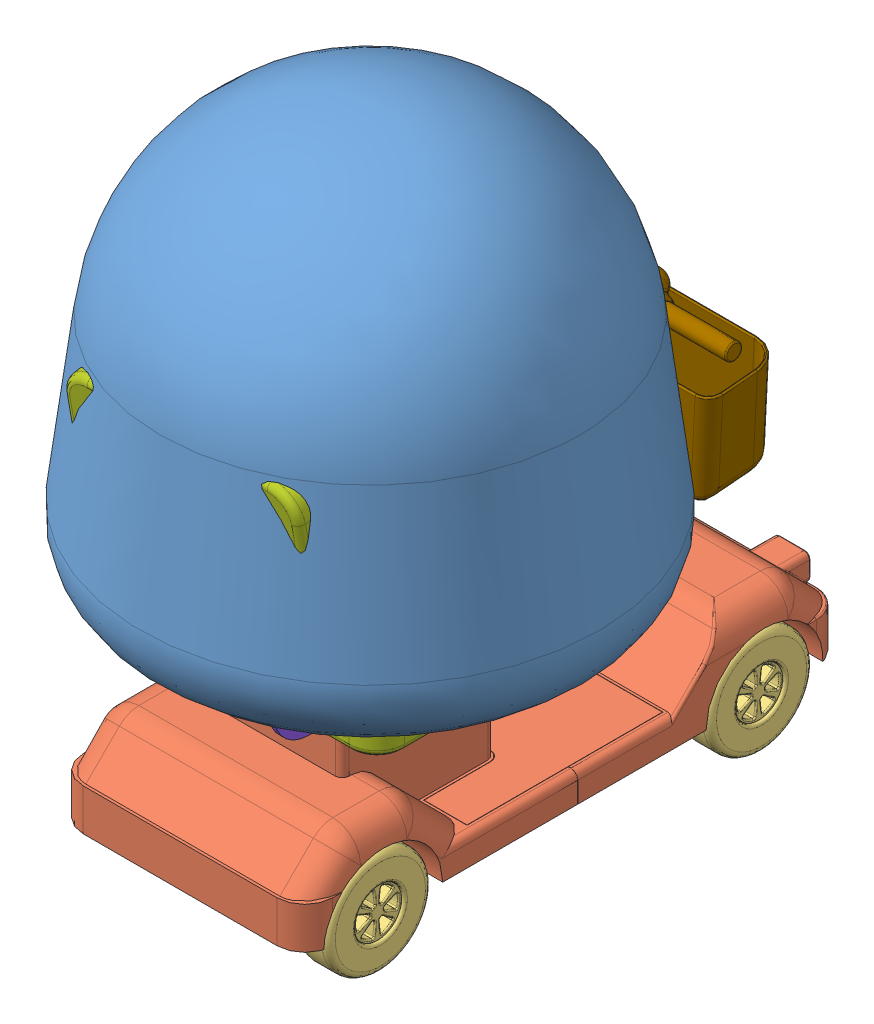
SolidWorks assembly pika_scoot_assy, configuration Default. Lengths in mm.
Overall size (331.68 462.3 417.84).
27 component instances, 10 part files, 24 mates.
Components (placement in the parent):
- pika-1: pika [Default] x (1 0 0) z (0 -1 0) size (331.68 331.68 304.8)
- scoot_skeleton-1: scoot_skeleton [Default] at origin
- scoot_chassis-1: scoot_chassis [Default] at origin size (189.55 105 389)
- wheel_assy-4: wheel_assy [Default] at (16.3417 0 -115) x (-1 0 0) z (0 0 -1) size (63 75 75)
  - wheel-1: wheel [Default] at (-58.6583 -272.4 -195) size (25 75 75)
  - 5972K501_Ball Bearing-1: 5972K501_Ball Bearing [5972K501] at (-54.6583 -272.4 -195) x (0 0 1) z (-1 0 0) size (22 22 7)
  - wheel_axle^wheel_assy-1: wheel_axle^wheel_assy [Default] at (-58.1583 -272.4 -195) x (1 0 0) z (0 0.886891 0.461979) size (50 8 8) (virtual)
  - axle_bracket-1: axle_bracket [Default] at (-8.1583 -272.4 -195) size (25.5 6.7 30)
- scoot_chair-1: scoot_chair [Default] at origin size (170 200.76 219.14)
- seat_bracket-1: seat_bracket [Default] at (-38 0 0) size (3.8 150.5 151.25)
- seat_bracket-2: seat_bracket [Default] at (38 0 0) size (3.8 150.5 151.25)
- wheel_assy-1: wheel_assy [Default] at (-16.3417 0 0) size (63 75 75)
  - wheel-1: wheel [Default] at (-58.6583 -272.4 -195) size (25 75 75)
  - 5972K501_Ball Bearing-1: 5972K501_Ball Bearing [5972K501] at (-54.6583 -272.4 -195) x (0 0 1) z (-1 0 0) size (22 22 7)
  - wheel_axle^wheel_assy-1: wheel_axle^wheel_assy [Default] at (-58.1583 -272.4 -195) x (1 0 0) z (0 0.886891 0.461979) size (50 8 8) (virtual)
  - axle_bracket-1: axle_bracket [Default] at (-8.1583 -272.4 -195) size (25.5 6.7 30)
- wheel_assy-2: wheel_assy [Default] at (-16.3417 0 275) size (63 75 75)
  - wheel-1: wheel [Default] at (-58.6583 -272.4 -195) size (25 75 75)
  - 5972K501_Ball Bearing-1: 5972K501_Ball Bearing [5972K501] at (-54.6583 -272.4 -195) x (0 0 1) z (-1 0 0) size (22 22 7)
  - wheel_axle^wheel_assy-1: wheel_axle^wheel_assy [Default] at (-58.1583 -272.4 -195) x (1 0 0) z (0 0.886891 0.461979) size (50 8 8) (virtual)
  - axle_bracket-1: axle_bracket [Default] at (-8.1583 -272.4 -195) size (25.5 6.7 30)
- wheel_assy-3: wheel_assy [Default] at (16.3417 0 -390) x (-1 0 0) z (0 0 -1) size (63 75 75)
  - wheel-1: wheel [Default] at (-58.6583 -272.4 -195) size (25 75 75)
  - 5972K501_Ball Bearing-1: 5972K501_Ball Bearing [5972K501] at (-54.6583 -272.4 -195) x (0 0 1) z (-1 0 0) size (22 22 7)
  - wheel_axle^wheel_assy-1: wheel_axle^wheel_assy [Default] at (-58.1583 -272.4 -195) x (1 0 0) z (0 0.886891 0.461979) size (50 8 8) (virtual)
  - axle_bracket-1: axle_bracket [Default] at (-8.1583 -272.4 -195) size (25.5 6.7 30)
- handlebars-1: handlebars [Default] at (0 -212.4 -211.7157) x (-1 0 0) z (0 0 -1) size (180 213.64 88.47)
Mates (geometry in assembly coordinates):
- Coincident1: coordinate: point of assembly; point of pika-1; point of assembly
- Parallel1: parallel aligned: plane of pika-1 through (0 0 0) normal (0 0 1)
- Parallel2: parallel anti-aligned: plane of pika-1 through (0 0 0) normal (0 -1 0)
- Distance1: distance = 0.1 mm anti-aligned: plane of seat_bracket^pika_scoot_assy-1 through (-39.9 -157.4 84.1955) normal (-1 0 0); plane of scoot_chair-1 through (-40 -157.4 84.1955) normal (1 0 0)
- Distance2: distance = 0.1 mm anti-aligned: plane of seat_bracket-2 through (39.9 -157.4 84.1955) normal (1 0 0); plane of scoot_chair-1 through (40 -157.4 84.1955) normal (-1 0 0)
- Coincident2: coincident aligned: plane of seat_bracket-1 through (-38 0 0) normal (0 1 0); plane of seat_bracket-2 through (38 0 0) normal (0 1 0)
- Coincident3: coincident aligned: plane of seat_bracket-1 through (-38 0 0) normal (0 0 1); plane of seat_bracket-2 through (38 0 0) normal (0 0 1)
- Coincident7: coincident: unknown of ?; plane of wheel_assy-1/wheel-1 through (-75 -272.4 -195) normal (0 0 1)
- Coincident8: coincident: unknown of ?; plane of wheel_assy-1/wheel-1 through (-75 -272.4 -195) normal (0 1 0)
- Distance4: distance = 25 mm anti-aligned: plane of Assem1^pika_scoot_assy-1/wheel-1 through (-75 -272.4 -195) normal (1 0 0); plane of scoot_chassis-1 through (-50 0 0) normal (-1 0 0)
- Coincident12: coincident anti-aligned: plane of scoot_chassis-1 through (50 -272.4 0) normal (0 -1 0); plane of wheel_assy-1/Copy of axle_bracket^wheel_assy-1 through (-24.5 -272.4 -195) normal (0 1 0)
- Coincident13: coincident: unknown of ?; plane of wheel_assy-1/axle_bracket-1 through (-24.5 -272.4 -195) normal (0 0 1)
- Concentric1: concentric anti-aligned: cylinder of scoot_chassis-1 through (-42.5 -262.4 90) axis (0 -1 0) radius 1.7; cylinder of wheel_assy-2/axle_bracket-1 through (-42.5 -279.5 90) axis (0 1 0) radius 1.7
- Concentric2: concentric anti-aligned: cylinder of scoot_chassis-1 through (-30.5 -262.4 70) axis (0 -1 0) radius 1.7; cylinder of wheel_assy-2/axle_bracket-1 through (-30.5 -279.5 70) axis (0 1 0) radius 1.7
- Concentric3: concentric aligned: cone of scoot_chassis-1 through (42.5 -272.4 -205) axis (0 1 0); cylinder of wheel_assy-3/axle_bracket-1 through (42.5 -279.5 -205) axis (0 1 0) radius 1.7
- Concentric4: concentric anti-aligned: cylinder of scoot_chassis-1 through (30.5 -262.4 -185) axis (0 -1 0) radius 1.7; cylinder of wheel_assy-3/axle_bracket-1 through (30.5 -279.5 -185) axis (0 1 0) radius 1.7
- Concentric5: concentric anti-aligned: circle of scoot_chassis-1; cylinder of wheel_assy-3/wheel_axle^wheel_assy-1 through (24.5 -272.4 -195) axis (1 0 0) radius 4
- Concentric6: concentric aligned: circle of scoot_chassis-1; circle of wheel_assy-2/wheel_axle^wheel_assy-1
- Concentric7: concentric anti-aligned: cylinder of scoot_chassis-1 through (30.5 -262.4 90) axis (0 -1 0) radius 1.7; cylinder of wheel_assy-4/axle_bracket-1 through (30.5 -279.5 90) axis (0 1 0) radius 1.7
- Concentric8: concentric anti-aligned: cylinder of scoot_chassis-1 through (42.5 -262.4 70) axis (0 -1 0) radius 1.7; cylinder of wheel_assy-4/axle_bracket-1 through (42.5 -279.5 70) axis (0 1 0) radius 1.7
- Concentric9: concentric anti-aligned: circle of scoot_chassis-1; circle of wheel_assy-4/wheel_axle^wheel_assy-1
- Coincident18: coincident aligned: plane of scoot_chassis-1 through (50 -212.4 0) normal (0 1 0); plane of handlebars-1 through (0 -212.4 -211.7157) normal (0 1 0)
- Coincident19: coincident: line of scoot_chassis-1 through (70 -212.4 -211.7157) axis (-1 0 0); plane of handlebars-1 through (0 -212.4 -211.7157) normal (0 0 -1)
- Coincident20: coincident anti-aligned: plane of handlebars-1 through (0 -212.4 -211.7157) normal (-1 0 0)
